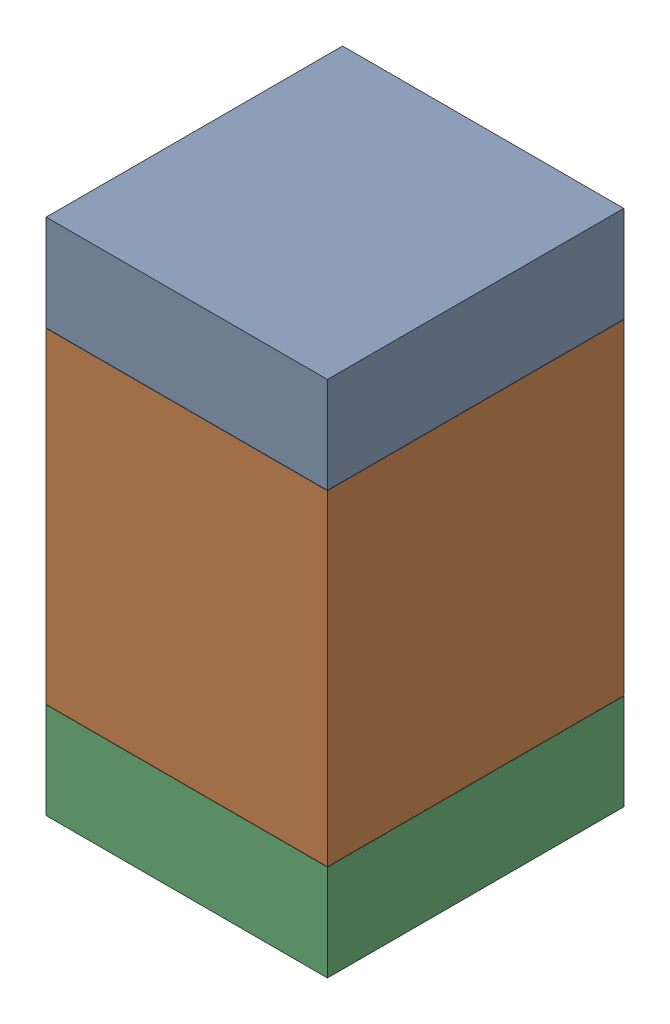
SolidWorks assembly C14, configuration Default. Lengths in mm.
Overall size (0.95 1.75 1).
6 component instances, 2 part files, 0 mates.
Components (placement in the parent):
- 6575495072-1: 6575495072 [Default] at (9.652 12.3965 0) size (0.95 0.32 1)
  - Extruded_6-1: Extruded_6 [Default] at origin size (0.95 0.32 1)
- 6575494912-1: 6575494912 [Default] at (9.652 11.684 0) size (0.95 1.1 1)
  - Extruded_7-1: Extruded_7 [Default] at origin size (0.95 1.1 1)
- 6575495072-2: 6575495072 [Default] at (9.652 10.9715 0) size (0.95 0.32 1)
  - Extruded_6-1: Extruded_6 [Default] at origin size (0.95 0.32 1)
